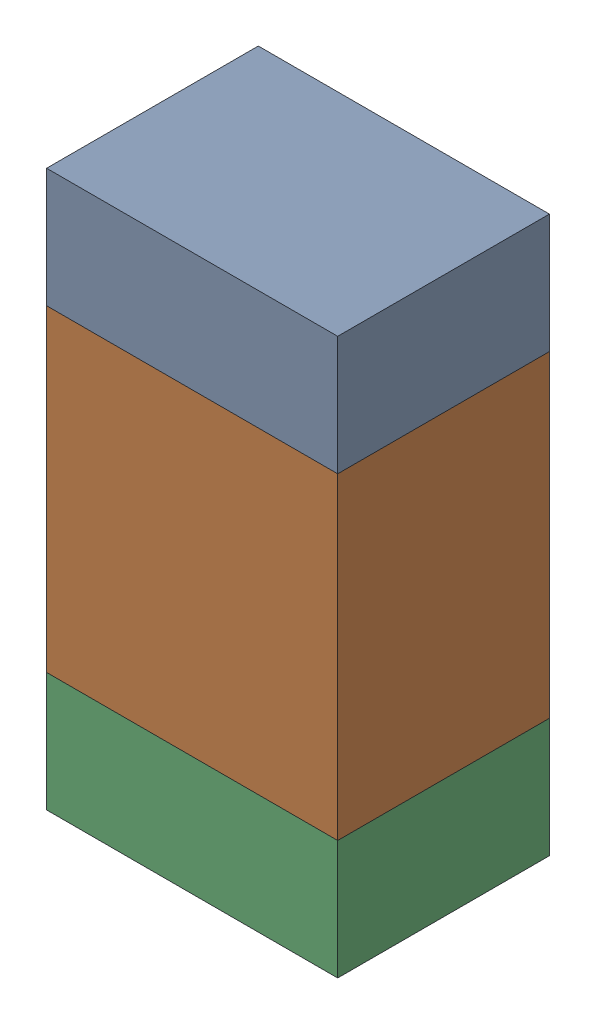
SolidWorks assembly R400PCB, configuration Default. Lengths in mm.
Overall size (0.55 1.05 0.4).
6 component instances, 2 part files, 0 mates.
Components (placement in the parent):
- 846483288-1: 846483288 [Default] at (79.9001 85.3124 0) size (0.55 0.22 0.4)
  - Extruded_12-1: Extruded_12 [Default] at origin size (0.55 0.22 0.4)
- 846483424-1: 846483424 [Default] at (79.9001 84.8999 0) size (0.55 0.6 0.4)
  - Extruded_13-1: Extruded_13 [Default] at origin size (0.55 0.6 0.4)
- 846483288-2: 846483288 [Default] at (79.9001 84.4874 0) size (0.55 0.22 0.4)
  - Extruded_12-1: Extruded_12 [Default] at origin size (0.55 0.22 0.4)
